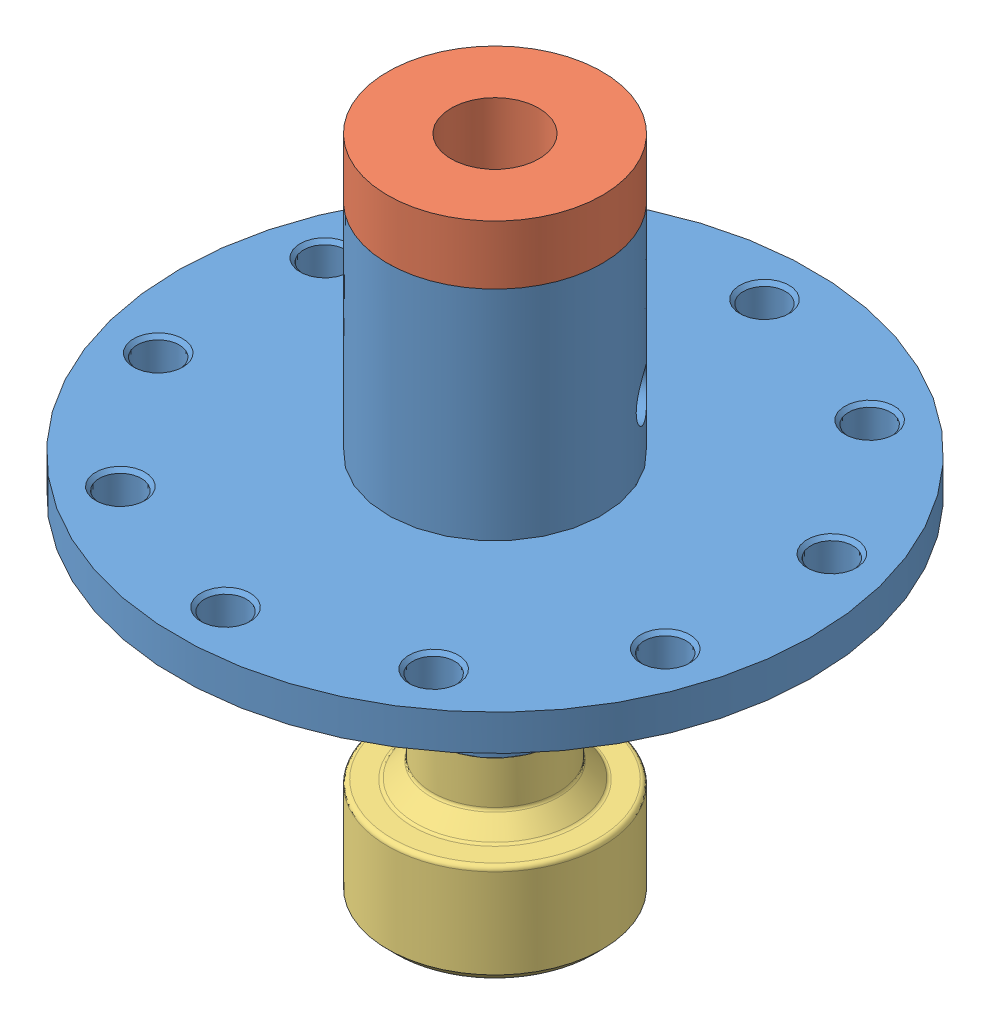
SolidWorks assembly 000012_R05_ASI_ASSEM, configuration Default. Lengths in mm.
Overall size (125.84 94.24 125.84).
3 component instances, 3 part files, 6 mates.
Components (placement in the parent):
- 000011-R07_ASI_TOP-1: 000011-R07_ASI_TOP [Default] x (0.583403 0 0.812183) z (-0.812183 0 0.583403) size (90.17 69.83 90.17)
- 000010-R02_ASI-1: 000010-R02_ASI [Default] at (0 25.4 0) x (-0.830204 0 0.55746) z (-0.55746 0 -0.830204) size (30.48 19.05 30.48)
- 000011-R04_ASI_BOTTOM-1: 000011-R04_ASI_BOTTOM [Default] at (0 -33.766 0) x (0.929472 0 0.368892) z (-0.368892 0 0.929472) size (30.48 23.65 30.48)
Mates (geometry in assembly coordinates):
- Concentric7: concentric aligned: circle of 000011-R07_ASI_TOP-1
- Coincident13: coincident: plane of 000011-R07_ASI_TOP-1 through (0 -33.766 0) normal (0 -1 0)
- Concentric8: concentric aligned: cylinder of 000011-R07_ASI_TOP-1 through (0 9.944 0) axis (0 -1 0) radius 15.24; cylinder of 000010-R02_ASI-1 through (0 43.18 0) axis (0 -1 0) radius 12.065
- Coincident15: coincident anti-aligned: plane of 000011-R07_ASI_TOP-1 through (8.8911 36.068 12.3777) normal (0 1 0); plane of 000010-R02_ASI-1 through (0 36.068 0) normal (0 -1 0)
- Concentric9: concentric aligned: cylinder of 000011-R07_ASI_TOP-1 through (0 9.944 0) axis (0 -1 0) radius 7.62; cylinder of 000011-R04_ASI_BOTTOM-1 through (0 -1066.786 0) axis (0 -1 0) radius 8.89
- Coincident16: coincident anti-aligned: plane of 000011-R07_ASI_TOP-1 through (4.4455 -26.146 6.1888) normal (0 -1 0); plane of 000011-R04_ASI_BOTTOM-1 through (5.9022 -26.146 2.3425) normal (0 1 0)
